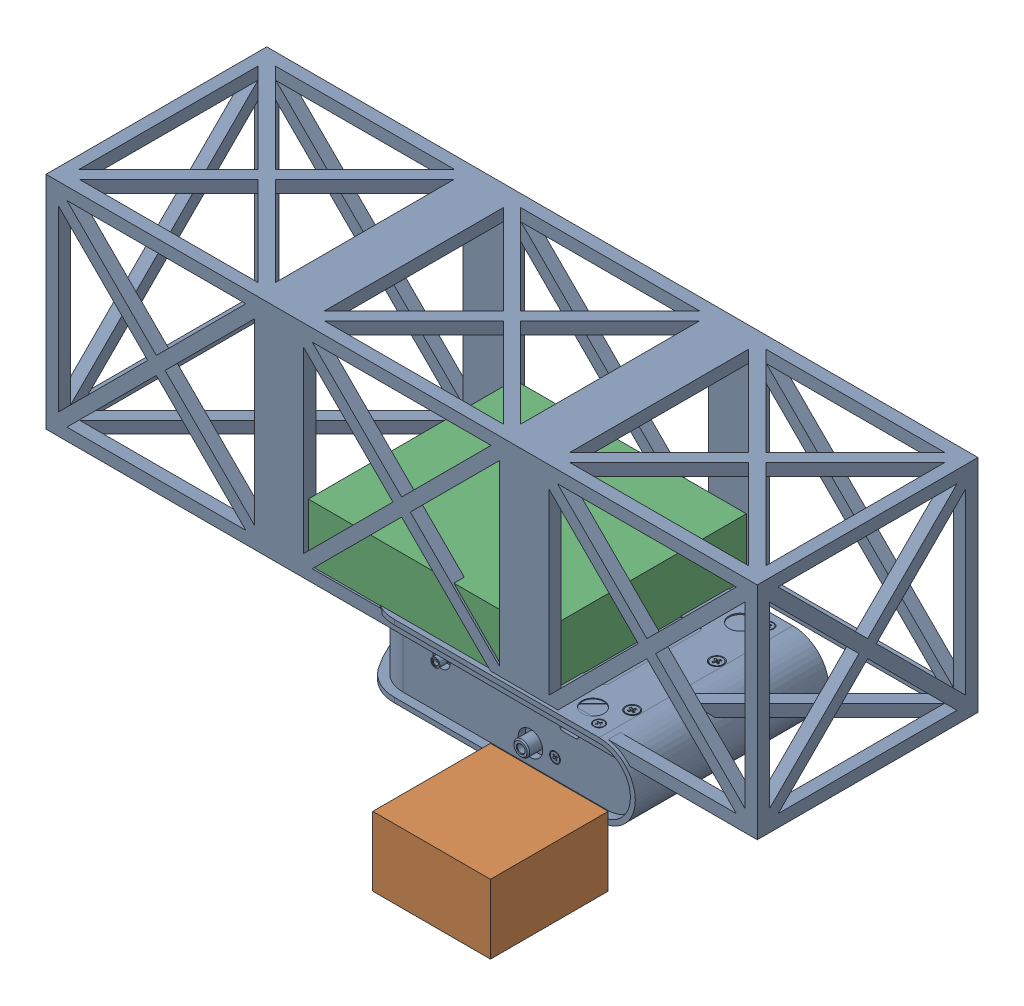
SolidWorks assembly 3U Satellite Assembly 1, configuration Default. Lengths in mm.
Overall size (290 114.29 196.38).
4 component instances, 4 part files, 2 mates.
Components (placement in the parent):
- 3U Frame outline-1: 3U Frame outline [Default] at (19.8781 65.3904 97.1722) size (290 90 90)
- CCS100_M-Solidworks-1: CCS100_M-Solidworks [Standard] at (18.2576 10.8466 143.5286) size (122.02 29.5 79.5)
- Comat RW20 rough volume-1: Comat RW20 rough volume [Default] at (138.4845 44.3374 224.5559) size (48 28.2 48)
- B14-M45 14V Modular SmallSat Battery Rough volume-1: B14-M45 14V Modular SmallSat Battery Rough volume [Default] at (28.2837 36.8466 99.3387) x (0 0 -1) z (1 0 0) size (84.1 23.1 94.5)
Mates (geometry in assembly coordinates):
- Coincident2: coincident anti-aligned: plane of CCS100_M-Solidworks-1 through (83.2576 25.2966 122.5286) normal (0 1 0); plane of B14-M45 14V Modular SmallSat Battery Rough volume-1 through (28.2837 25.2966 99.3387) normal (0 -1 0)
- Coincident3: coincident anti-aligned: plane of 3U Frame outline-1 through (-120.1219 25.2966 137.1197) normal (0 1 0); plane of B14-M45 14V Modular SmallSat Battery Rough volume-1 through (28.2837 25.2966 99.3387) normal (0 -1 0)
